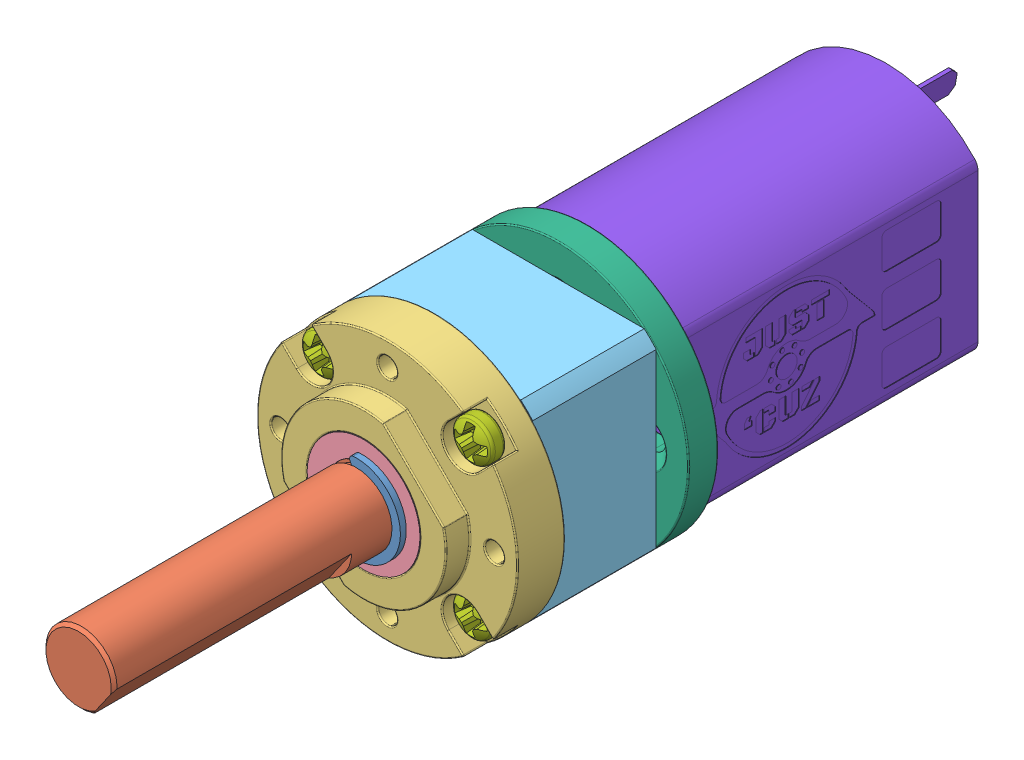
SolidWorks assembly DartBox V2 6mm Shaft, configuration Default. Lengths in mm.
Overall size (21.95 21.95 72.3).
16 component instances, 8 part files, 0 mates.
Components (placement in the parent):
- DartBox V2 6mm Shaft.stp-1: DartBox V2 6mm Shaft.stp [Default] at origin size (21.95 21.95 72.3)
  - DartBox V2 Drive 6mm Output.stp-1: DartBox V2 Drive 6mm Output.stp [Default] at (0 15.4164 54.362) x (0 1 0) z (0 0 1) size (21.95 21.95 42.9)
    - Ring Gear.stp-1: Ring Gear.stp [Default] at (-10.101 0.0152 -54.1116) x (0 -1 0) z (0 0 1) size (21.95 21.95 40.4)
      - Front Plate.stp-1: Front Plate.stp [Default] at (0.0152 10.101 56.6116) x (0 1 0) z (1 0 0) size (21.95 30.5 21.95)
        - Shaft.stp-1: Shaft.stp [Default] x (-0.819152 0 -0.573576) z (0.573576 0 -0.819152) size (7.4 30.3 6.7)
          - Retaining Ring.stp-1: Retaining Ring.stp [Default] at (0 16.65 0) x (-1 0 0) z (0 -1 0) size (7.4 6.16 0.5)
          - Shaft-0.stp-1: Shaft-0.stp [Default] at origin size (6 30.3 6)
        - Front Plate-1.stp-1: Front Plate-1.stp [Default] at origin size (21.95 6.5 21.95)
        - Front Plate-2.stp-1: Front Plate-2.stp [Default] at origin size (9.5 6 9.5)
      - Ring Gear Body.stp-1: Ring Gear Body.stp [Default] at (0.0152 10.101 56.6116) x (0 1 0) z (1 0 0) size (16.5 10.4 16.5)
    - Motor Mount Plate.stp-1: Motor Mount Plate.stp [Default] at (0 0 2.5) x (1 0 0) z (0 -1 0) size (21.95 3.5 21.95)
    - Screws M2 x 14mm.stp-1: Screws M2 x 14mm.stp [Default] at (6.364 6.364 0.9) size (3.4 3.4 15.61)
    - Screws M2 x 14mm.stp-2: Screws M2 x 14mm.stp [Default] at (-6.364 6.364 0.9) x (0 1 0) z (0 0 1) size (3.4 3.4 15.61)
    - Screws M2 x 14mm.stp-3: Screws M2 x 14mm.stp [Default] at (-6.364 -6.364 0.9) x (-1 0 0) z (0 0 1) size (3.4 3.4 15.61)
    - Screws M2 x 14mm.stp-4: Screws M2 x 14mm.stp [Default] at (6.364 -6.364 0.9) x (0 -1 0) z (0 0 1) size (3.4 3.4 15.61)
  - DartBox 130 motor.stp-1: DartBox 130 motor.stp [Default] at (0 15.4164 54.362) x (1 0 0) z (0 0 -1) size (15.5 20.4 34.9)
